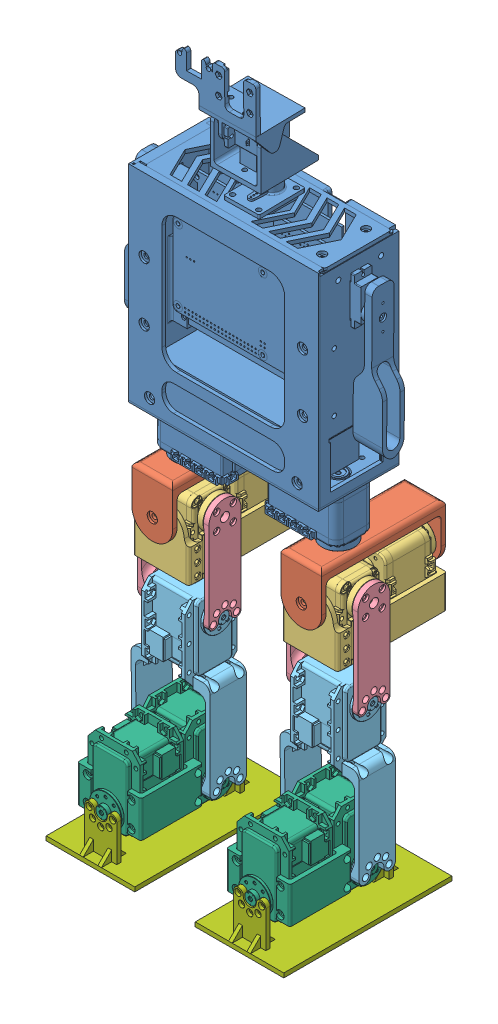
SolidWorks assembly robo, configuration Valor predeterminado. Lengths in mm.
Overall size (177 477.9 127.05).
13 component instances, 7 part files, 26 mates.
Components (placement in the parent):
- torso-1: torso [Valor predeterminado] at (20.5077 13.8 -4.5855) x (1 0 0) z (0 1 0) size (177 55.25 266.26)
- perna5-1: perna5 [Valor predeterminado] at (-55.6635 -94.8554 -56.5) size (28 40 84.75)
- perna4-1: perna4 [Valor predeterminado] at (-51 -62.75 0) x (-1 0 0) z (0 0 -1) size (40.37 50 75.75)
- perna3-1: perna3 [Valor predeterminado] at (-51 -62.75 0) x (-1 0 0) z (0 0 -1) size (49 82 22)
- perna2-1: perna2 [Valor predeterminado] at (-51 -62.75 0) x (-1 0 0) z (0 0 -1) size (53.91 122.24 35.6)
- perna1-1: perna1 [Valor predeterminado] at (-51 -62.75 0) x (-1 0 0) z (0 0 -1) size (45.4 50.71 81.2)
- pe-1: pe [Valor predeterminado] at (-51 -220.3883 57.55) x (-1 0 0) z (0 0 1) size (60.6 39 115)
- perna5-2: perna5 [Valor predeterminado] at (46.3365 -94.8554 -56.5) size (28 40 84.75)
- perna4-2: perna4 [Valor predeterminado] at (51 -62.75 0) x (-1 0 0) z (0 0 -1) size (40.37 50 75.75)
- perna3-2: perna3 [Valor predeterminado] at (51 -62.75 0) x (-1 0 0) z (0 0 -1) size (49 82 22)
- perna2-2: perna2 [Valor predeterminado] at (51 -62.75 0) x (-1 0 0) z (0 0 -1) size (53.91 122.24 35.6)
- perna1-2: perna1 [Valor predeterminado] at (51 -62.75 0) x (-1 0 0) z (0 0 -1) size (45.4 50.71 81.2)
- pe-2: pe [Valor predeterminado] at (51 -220.3883 57.55) x (-1 0 0) z (0 0 1) size (60.6 39 115)
Mates (geometry in assembly coordinates):
- Coincidente2: coincident anti-aligned: plane of torso-1 through (-52.9555 -36.75 -1.9335) normal (0 -1 0); plane of perna5-1 through (-63 -36.75 -59.5) normal (0 1 0)
- Concêntrico1: concentric aligned: cylinder of torso-1 through (-51 -36.75 0) axis (0 1 0) radius 2.75; cylinder of perna5-1 through (-51 -39.75 0) axis (0 1 0) radius 3
- Distância1: distance = 0.25 mm anti-aligned: plane of perna4-1 through (-49.0665 -60.7945 -56.25) normal (0 0 -1); plane of perna5-1 through (-51 -62.75 -56.5) normal (0 0 1)
- Concêntrico2: concentric aligned: cylinder of perna5-1 through (-51 -62.75 -59.5) axis (0 0 1) radius 3.05; cylinder of perna4-1 through (-51 -62.75 -56.25) axis (0 0 1) radius 2.75
- Coincidente5: coincident anti-aligned: plane of perna4-1 through (-30.25 -60.7945 1.9335) normal (1 0 0); plane of perna3-1 through (-30.25 -60.7945 1.9335) normal (-1 0 0)
- Concêntrico3: concentric anti-aligned: cylinder of perna4-1 through (-30.25 -62.75 0) axis (-1 0 0) radius 2.75; cylinder of perna3-1 through (-30.25 -62.75 0) axis (1 0 0) radius 3.05
- Coincidente7: coincident anti-aligned: plane of perna3-1 through (-30.25 -122.75 3.875) normal (-1 0 0); plane of perna2-1 through (-30.25 -122.75 0) normal (1 0 0)
- Concêntrico4: concentric aligned: cylinder of perna3-1 through (-1.2881 -122.75 0) axis (-1 0 0) radius 4.5; cylinder of perna2-1 through (-27.1075 -122.75 0) axis (-1 0 0) radius 4
- Coincidente9: coincident anti-aligned: plane of perna2-1 through (-30.25 -220.3883 4.25) normal (-1 0 0); plane of perna1-1 through (-30.25 -220.3883 0) normal (1 0 0)
- Concêntrico5: concentric aligned: cylinder of perna2-1 through (4.7541 -220.3883 0) axis (-1 0 0) radius 4.5; cylinder of perna1-1 through (-27.1075 -220.3883 0) axis (-1 0 0) radius 4
- Distância2: distance = 0.25 mm anti-aligned: plane of pe-1 through (-58.75 -220.3883 57.55) normal (0 0 -1); plane of perna1-1 through (-51 -220.3883 57.3) normal (0 0 1)
- Concêntrico7: concentric aligned: cylinder of perna1-1 through (-51 -220.3883 60.4425) axis (0 0 -1) radius 4; cylinder of pe-1 through (-51 -220.3883 60.55) axis (0 0 -1) radius 4.5
- Coincidente13: coincident anti-aligned: plane of torso-1 through (52.9555 -36.75 1.9335) normal (0 -1 0); plane of perna5-2 through (39 -36.75 -59.5) normal (0 1 0)
- Concêntrico8: concentric aligned: cylinder of torso-1 through (51 -36.75 0) axis (0 1 0) radius 2.75; cylinder of perna5-2 through (51 -39.75 0) axis (0 1 0) radius 3
- Distância3: distance = 0.25 mm anti-aligned: plane of perna4-2 through (52.9335 -60.7945 -56.25) normal (0 0 -1); plane of perna5-2 through (51 -62.75 -56.5) normal (0 0 1)
- Concêntrico9: concentric aligned: cylinder of perna5-2 through (51 -62.75 -59.5) axis (0 0 1) radius 3.05; cylinder of perna4-2 through (51 -62.75 -56.25) axis (0 0 1) radius 2.75
- Coincidente14: coincident anti-aligned: plane of perna4-2 through (71.75 -60.7945 1.9335) normal (1 0 0); plane of perna3-2 through (71.75 -60.7945 1.9335) normal (-1 0 0)
- Concêntrico10: concentric anti-aligned: cylinder of perna4-2 through (71.75 -62.75 0) axis (-1 0 0) radius 2.75; cylinder of perna3-2 through (71.75 -62.75 0) axis (1 0 0) radius 3.05
- Coincidente15: coincident anti-aligned: plane of perna3-2 through (71.75 -122.75 3.875) normal (-1 0 0); plane of perna2-2 through (71.75 -122.75 0) normal (1 0 0)
- Concêntrico11: concentric aligned: cylinder of perna3-2 through (100.7119 -122.75 0) axis (-1 0 0) radius 4.5; cylinder of perna2-2 through (74.8925 -122.75 0) axis (-1 0 0) radius 4
- Coincidente16: coincident anti-aligned: plane of perna2-2 through (71.75 -220.2781 -6.2898) normal (-1 0 0); plane of perna1-2 through (71.75 -219.8204 -10.5151) normal (1 0 0)
- Concêntrico12: concentric aligned: cylinder of perna2-2 through (106.7541 -219.8204 -10.5151) axis (-1 0 0) radius 4.5; cylinder of perna1-2 through (74.8925 -219.8204 -10.5151) axis (-1 0 0) radius 4
- Distância4: distance = 0.25 mm anti-aligned: plane of pe-2 through (43.25 -220.3883 57.55) normal (0 0 -1); plane of perna1-2 through (51 -220.3883 57.3) normal (0 0 1)
- Concêntrico13: concentric aligned: cylinder of perna1-2 through (51 -219.8204 49.9274) axis (0 0 -1) radius 4; cylinder of pe-2 through (51 -219.8204 50.0349) axis (0 0 -1) radius 4.5
- Paralelo12: parallel aligned: plane of perna4-2 through (51 -85.5 19.5) normal (0 0 1); plane of perna3-2 through (75.5 -62.75 11) normal (0 0 1)
- Paralelo13: parallel aligned: plane of perna3-2 through (75.5 -62.75 11) normal (0 0 1); plane of perna2-2 through (77.8 -156 12.5) normal (0 0 1)
